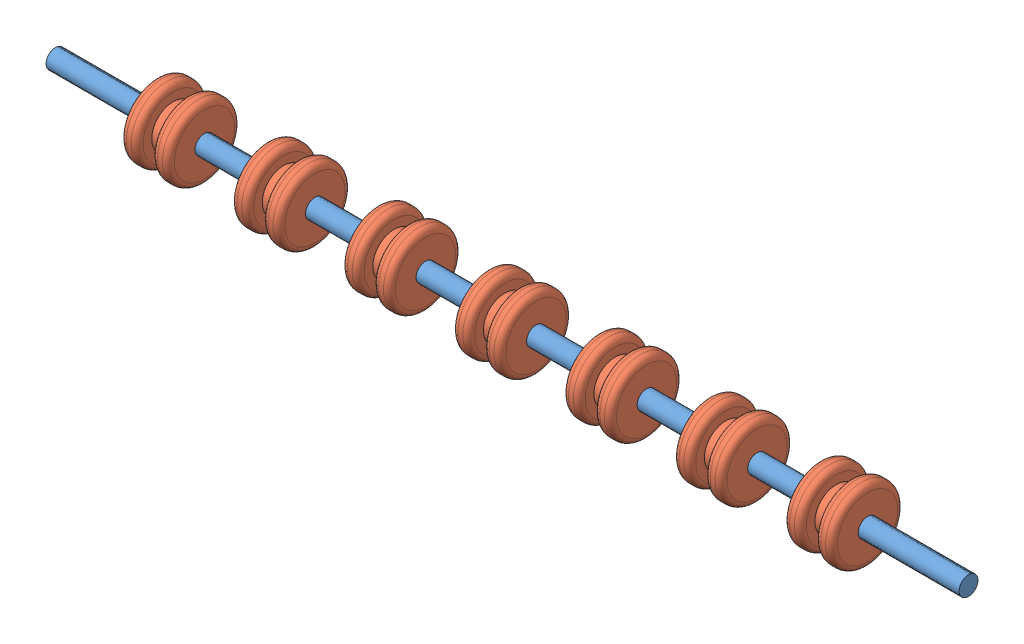
SolidWorks assembly Idler Assy, configuration Default. Lengths in mm.
Overall size (241.3 19.56 19.56).
8 component instances, 2 part files, 2 mates.
Components (placement in the parent):
- Idler Shaft-1: Idler Shaft [Default] at origin size (241.3 5 5)
- Idler-1: Idler [Default] at origin size (13.21 19.56 19.56)
- Idler-2: Idler [Default] at (-29.21 0 0) size (13.21 19.56 19.56)
- Idler-3: Idler [Default] at (-58.42 0 0) size (13.21 19.56 19.56)
- Idler-4: Idler [Default] at (-87.63 0 0) size (13.21 19.56 19.56)
- Idler-6: Idler [Default] at (29.21 0 0) x (-1 0 0) z (0 0 -1) size (13.21 19.56 19.56)
- Idler-7: Idler [Default] at (58.42 0 0) x (-1 0 0) z (0 0 -1) size (13.21 19.56 19.56)
- Idler-8: Idler [Default] at (87.63 0 0) x (-1 0 0) z (0 0 -1) size (13.21 19.56 19.56)
Mates (geometry in assembly coordinates):
- Concentric1: concentric aligned: cylinder of Idler Shaft-1 through (120.65 0 0) axis (-1 0 0) radius 2.5; cylinder of Idler-1 through (6.604 0 0) axis (-1 0 0) radius 2.5
- Coincident2: coincident aligned: plane of Idler-1 through (0 0 0) normal (1 0 0); plane of assembly through (0 0 0) normal (1 0 0)
